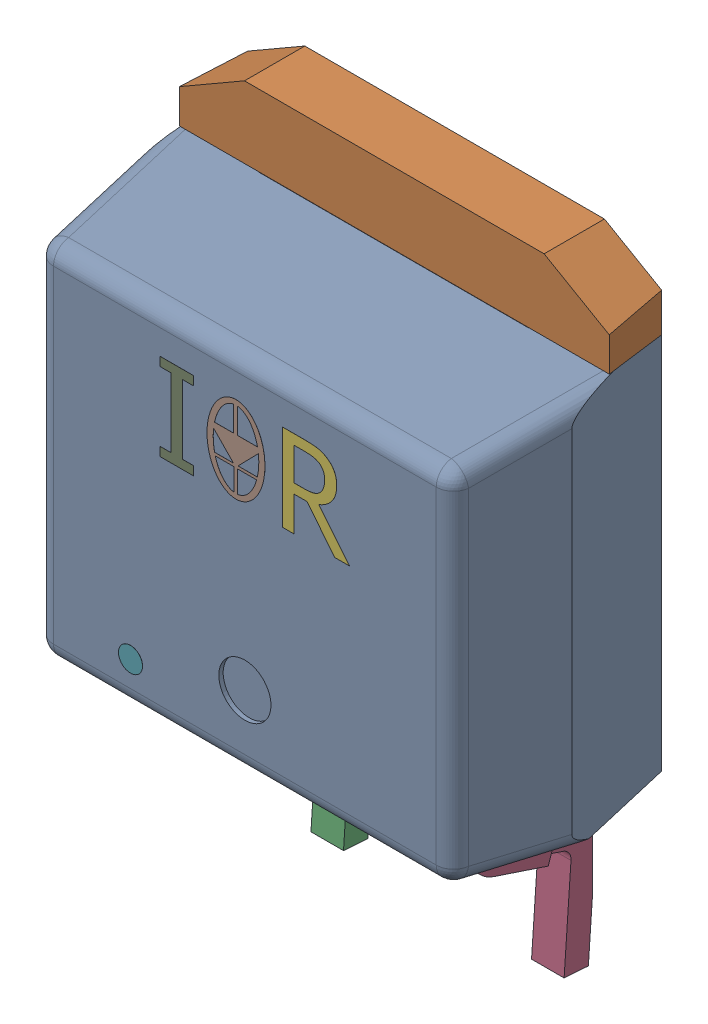
SolidWorks assembly Trans_Infineon_IRF2805STRLPBF_eec.step, configuration Default. Lengths in mm.
Overall size (10.16 15.25 5.09).
4 component instances, 4 part files, 0 mates.
Components (placement in the parent):
- 1-0.step-1: 1-0.step [Default] at (0 0 2.633) x (1 0 0) z (0 -1 0) size (10.16 4.83 9.02)
- 2-1.step-1: 2-1.step [Default] at (0 0 2.633) x (1 0 0) z (0 -1 0) size (9.9 1.4 6.86)
- 3-2.step-1: 3-2.step [Default] at (0 0 2.633) x (1 0 0) z (0 -1 0) size (6.54 3.17 4.65)
- IRF_logo.step-1: IRF_logo.step [Default] at (1.3993 2.6618 4.985) size (5.32 6.67 0.1)
